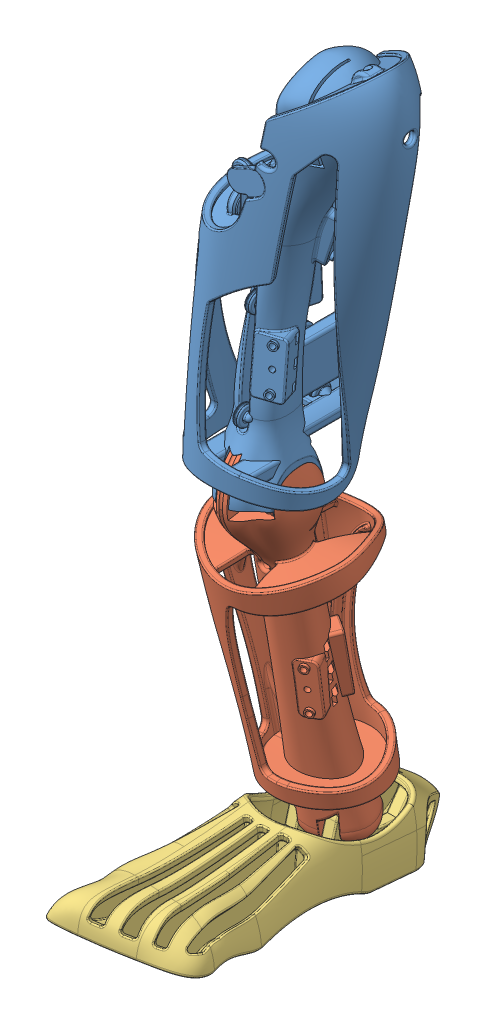
SolidWorks assembly a-bein-links-v01, configuration 01. Lengths in mm.
Overall size (216.77 629.45 244.04).
3 component instances, 3 part files, 9 mates.
Components (placement in the parent):
- p-oberschenkel-v02-1: p-oberschenkel-v02 [links01] x (-1 0 0) z (0 0 -1) size (216.77 572 184.25)
- p-unterschenkel-v02-1: p-unterschenkel-v02 [links01] at (0 -3.95 45.1485) x (-1 0 0) z (0 0.173648 -0.984808) size (104.62 295.08 116.44)
- p-fuss-links-v12-1: p-fuss-links-v12 [01] at (11 -481.5492 -26.9812) x (-1 0 0) z (0 -0.087156 -0.996195) size (88.74 74.5 238.45)
Mates (geometry in assembly coordinates):
- Deckungsgleich2: coincident anti-aligned: plane of p-oberschenkel-v02-1 through (0 0 0) normal (0 0 -1); plane of assembly through (0 0 0) normal (0 0 1)
- Deckungsgleich3: coincident aligned: plane of p-oberschenkel-v02-1; plane of assembly through (0 0 0) normal (0 1 0)
- Deckungsgleich4: coincident anti-aligned: plane of p-oberschenkel-v02-1 through (0 0 0) normal (-1 0 0); plane of assembly through (0 0 0) normal (1 0 0)
- Konzentrisch1: concentric aligned: cylinder of p-oberschenkel-v02-1 through (-49.3583 -260 0) axis (1 0 0) radius 7.9; cylinder of p-unterschenkel-v02-1 through (-43.0818 -260 0) axis (1 0 0) radius 7.1
- Deckungsgleich5: coincident aligned: plane of p-oberschenkel-v02-1 through (0 0 0) normal (-1 0 0); plane of p-unterschenkel-v02-1
- Winkel1: planar angle = 0.174533 rad anti-aligned: plane of p-unterschenkel-v02-1 through (0 -305.1485 256.05) normal (0 0.984808 0.173648); plane of p-oberschenkel-v02-1 through (0 -260 260) normal (0 -1 0)
- Konzentrisch2: concentric aligned: cylinder of p-unterschenkel-v02-1 through (22 -488.4754 -40.2864) axis (-1 0 0) radius 7.5; cylinder of p-fuss-links-v12-1 through (21 -488.4754 -40.2864) axis (-1 0 0) radius 6.7
- Deckungsgleich6: coincident anti-aligned: plane of p-fuss-links-v12-1; plane of assembly through (0 0 0) normal (1 0 0)
- Winkel2: planar angle = 0.261799 rad anti-aligned: plane of p-fuss-links-v12-1; plane of p-unterschenkel-v02-1
